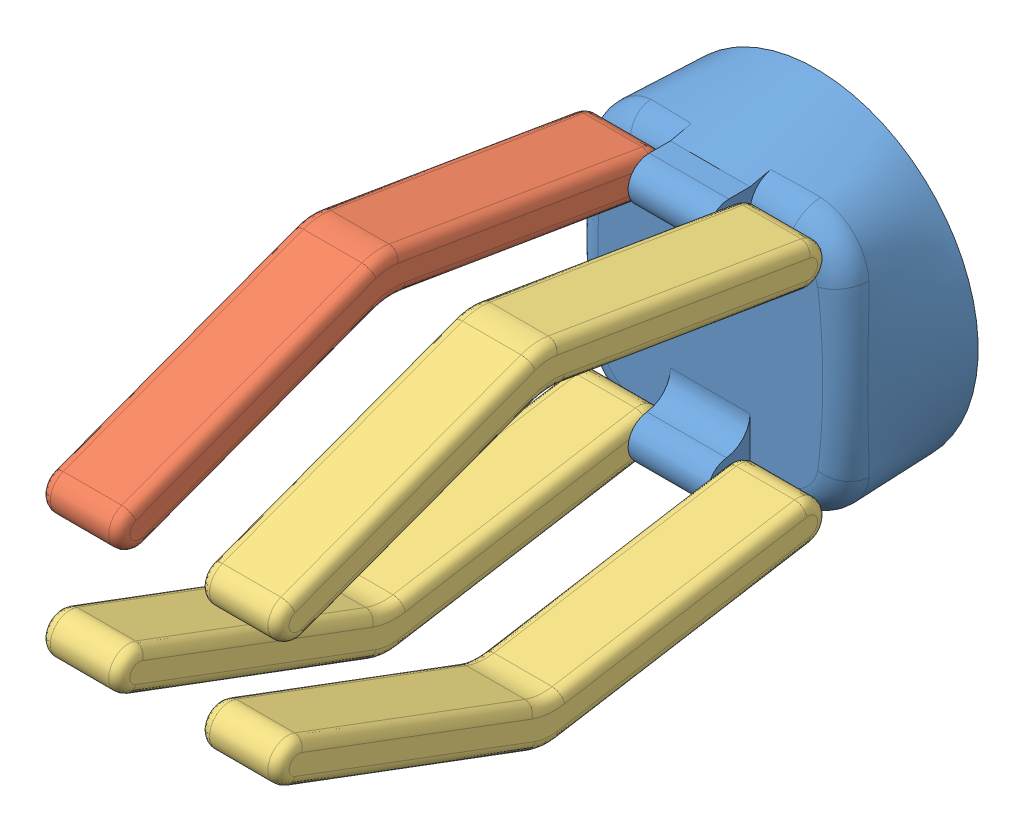
SolidWorks assembly gripper_assembly, configuration Default. Lengths in mm.
Overall size (61.02 88.27 126.08).
5 component instances, 3 part files, 2 mates.
Components (placement in the parent):
- gripper_palm-1: gripper_palm [Default] at origin size (61.02 61.02 28.01)
- gripper_finger-1: gripper_finger [Default] at (-15 21 24) x (1 0 0) z (0 -0.228379 0.973572) size (15 26.63 103.22)
- Mirrorgripper_finger-3: Mirrorgripper_finger [Default] at (15 21 24) x (-1 0 0) z (0 0.228379 -0.973572) size (15 26.63 103.22)
- Mirrorgripper_finger-5: Mirrorgripper_finger [Default] at (-15 -21 24) x (1 0 0) z (0 -0.228379 -0.973572) size (15 26.63 103.22)
- Mirrorgripper_finger-4: Mirrorgripper_finger [Default] at (15 -21 24) x (1 0 0) z (0 -0.228379 -0.973572) size (15 26.63 103.22)
Mates (geometry in assembly coordinates):
- Coincident1: coincident anti-aligned: plane of gripper_palm-1 through (-7.5 21 24) normal (-1 0 0); plane of gripper_finger-1 through (-7.5 15.0806 71.9496) normal (1 0 0)
- Concentric1: concentric aligned: cylinder of gripper_palm-1 through (7.5 21 24) axis (-1 0 0) radius 4; cylinder of gripper_finger-1 through (-7.5 21 24) axis (-1 0 0) radius 3.75
